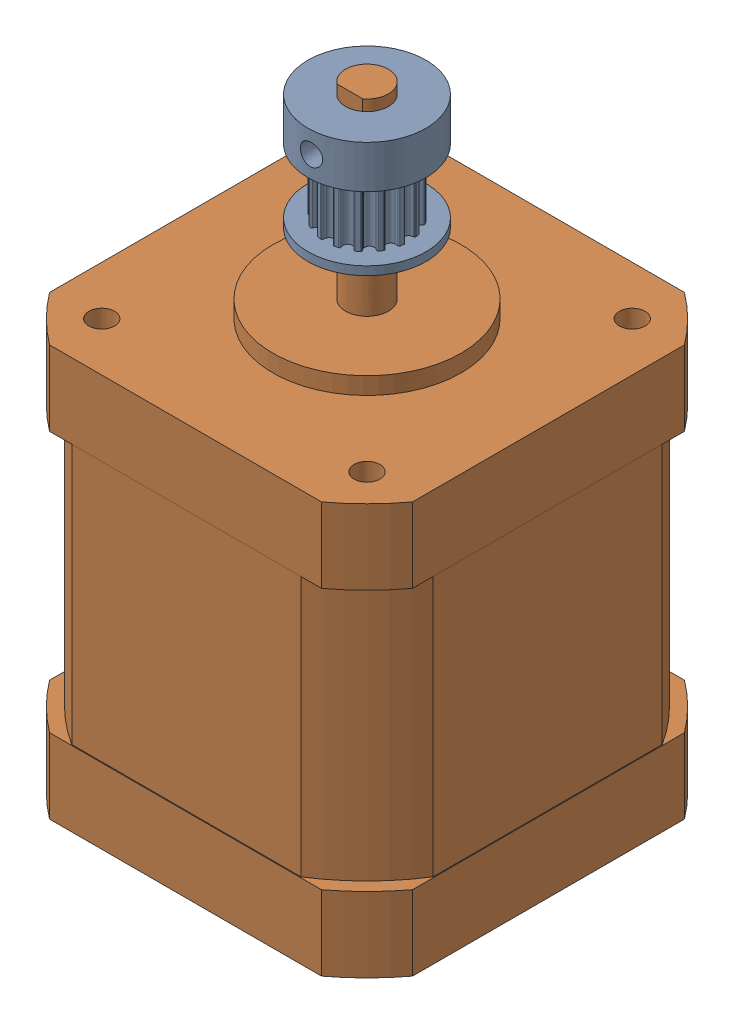
SolidWorks assembly xy_drive_stepper_2, configuration Default. Lengths in mm.
Overall size (42.42 72 42.42).
2 component instances, 2 part files, 0 mates.
Components (placement in the parent):
- drive_pulley_16t_gt2_6mm_belt-1: drive_pulley_16t_gt2_6mm_belt [Default] at (-27.429 406.7309 -32.1843) x (-0.044306 0 -0.999018) z (-0.999018 0 0.044306) size (13.8 13.5 13.8)
- 17HM19-2004S-1: 17HM19-2004S [Default] at (-27.429 384.0105 -32.1843) x (-1 0 0) z (0 1 0) size (42.42 42.42 72)
